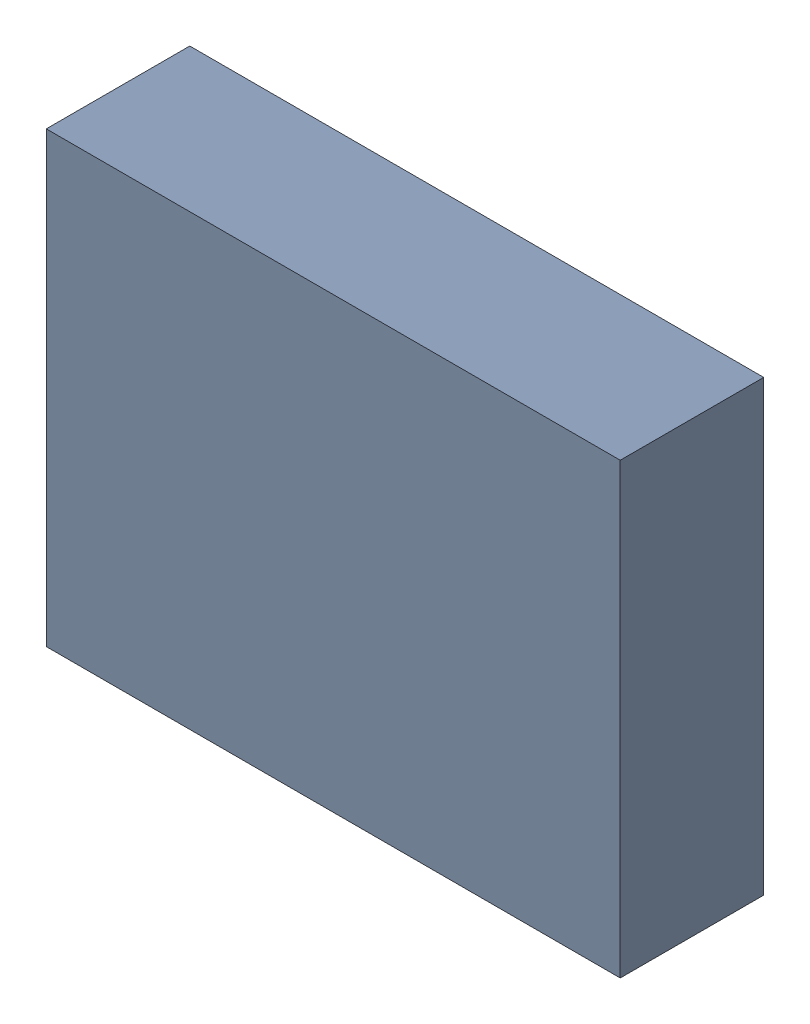
SolidWorks assembly X1, configuration Standard. Lengths in mm.
Overall size (3.2 2.5 0.8).
2 component instances, 1 part files, 0 mates.
Components (placement in the parent):
- 885545504-1: 885545504 [Standard] at (10.5 -1.45 0) size (3.2 2.5 0.8)
  - Extruded_6-1: Extruded_6 [Standard] at origin size (3.2 2.5 0.8)
